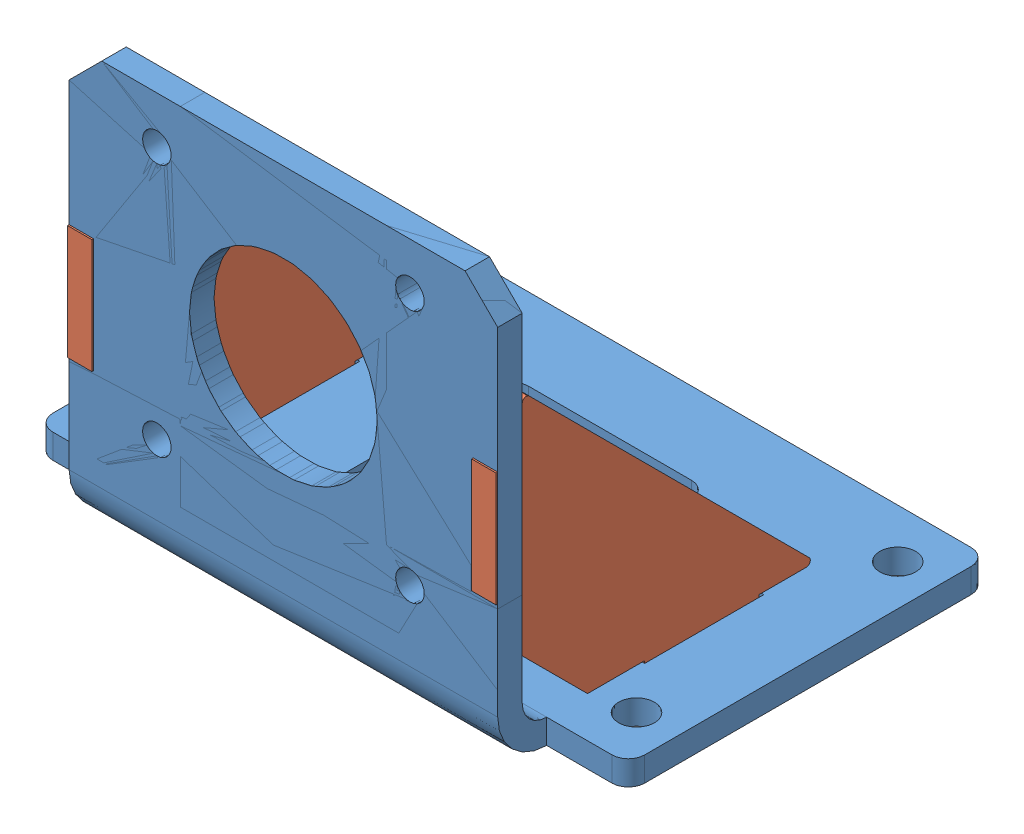
SolidWorks assembly NEMA_17_stand_welded_from_step, configuration ﾃﾞﾌｫﾙﾄ. Lengths in mm.
Overall size (72.5 51.55 50.2).
3 component instances, 2 part files, 0 mates.
Components (placement in the parent):
- 9241-01.02.01.02_Stojka_01-1: 9241-01.02.01.02_Stojka_01 [ﾃﾞﾌｫﾙﾄ] at (0 30.1 0) size (72.5 51.35 50)
- 9241-01.02.01.01_Planka_01-1: 9241-01.02.01.01_Planka_01 [ﾃﾞﾌｫﾙﾄ] at (-23.25 3 0) x (0 0 -1) z (1 0 0) size (38.49 38.49 3)
- 9241-01.02.01.01_Planka_01-2: 9241-01.02.01.01_Planka_01 [ﾃﾞﾌｫﾙﾄ] at (26.25 3 0) x (0 0 -1) z (1 0 0) size (38.49 38.49 3)
